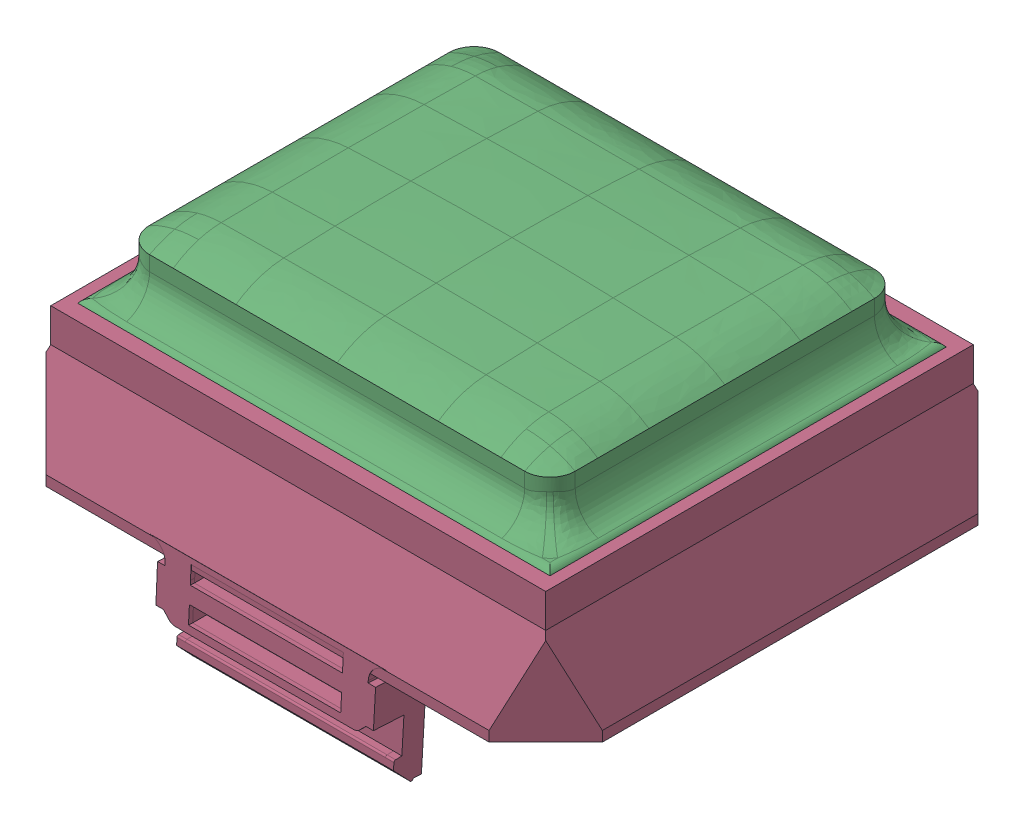
SolidWorks assembly ChessBDesign, configuration 默认. Lengths in mm.
Overall size (33 18.27 29.5).
5 component instances, 5 part files, 13 mates.
Components (placement in the parent):
- ChessBLens-1: ChessBLens [默认] at origin size (28.33 2.18 23.83)
- ChessBInsideSkin-1: ChessBInsideSkin [默认] at (0.0001 0 0.2499) size (23.8 5.48 19.29)
- ChessBTopskin-1: ChessBTopskin [默认] at (0.0001 2 0.2499) size (28.02 6.25 23.52)
- ChessBSupportbase-2: ChessBSupportbase [默认] at origin size (33 14.02 29.5)
- ChessBChessboardMarker-1: ChessBChessboardMarker [默认] at (-4.7946 24.2 -14.5409) x (1 0 0) z (0 -1 0) size (22.6 16.44 0.67)
Mates (geometry in assembly coordinates):
- 同心2: concentric anti-aligned: cylinder of InsideSkin-1 through (10.8751 17.7531 8.6249) axis (0 1 0) radius 0.7; cylinder of Board3Con1612611OriginalSkin_TOP-1 through (10.8751 24 8.6249) axis (0 -1 0) radius 0.7
- 同心3: concentric anti-aligned: cylinder of InsideSkin-1 through (10.8751 17.7531 -9.1251) axis (0 1 0) radius 0.7; cylinder of Board3Con1612611OriginalSkin_TOP-1 through (10.8751 24 -9.1251) axis (0 -1 0) radius 0.7
- 重合4: coincident aligned: plane of InsideSkin-1 through (10.8751 19 -9.1251) normal (0 -1 0); plane of Board3Con1612611OriginalSkin_TOP-1 through (0.0001 19 0.2499) normal (0 -1 0)
- 重合6: coordinate: point of NewContiSupportBase-2
- 重合7: coincident anti-aligned: plane of lensall-1 through (13.75 19 -11.5) normal (0.939693 0.34202 0); plane of NewContiSupportBase-2 through (13.75 19 12.7803) normal (-0.939693 -0.34202 0)
- 同心5: concentric aligned: cylinder of lensall-1 through (13.3294 18.6938 -11.0794) axis (-0.323616 0.889126 0.323616) radius 0.5; cylinder of NewContiSupportBase-2 through (10.7866 25.6801 -8.5366) axis (-0.323616 0.889126 0.323616) radius 0.5
- 重合8: coincident anti-aligned: plane of lensall-1 through (0 18 0) normal (0 -1 0); plane of NewContiSupportBase-2 through (0 18 0) normal (0 1 0)
- 重合9: coincident anti-aligned: plane of lensall-1 through (0 19 0) normal (0 1 0); plane of Board3Con1612611OriginalSkin_TOP-1 through (0.0001 19 0.2499) normal (0 -1 0)
- 重合10: coincident anti-aligned: plane of Board3Con1612611OriginalSkin_TOP-1 through (0.0001 19 11.7499) normal (0 0 1); plane of NewContiSupportBase-2 through (-13.5999 21 11.7499) normal (0 0 -1)
- 重合11: coincident anti-aligned: plane of Board3Con1612611OriginalSkin_TOP-1 through (14.0001 19 0.2499) normal (1 0 0); plane of NewContiSupportBase-2 through (14.0001 21 11.7499) normal (-1 0 0)
- 宽度1: width aligned: plane of InsideSkin-1 through (-11.3749 17.7531 9.3249) normal (0 0 1); plane of ChessboardMarker-1 through (-11.3749 17.7531 -9.8251) normal (0 0 -1); plane of InsideSkin-1 through (2.8501 23.8 7.9249) normal (0 0 1); plane of ChessboardMarker-1 through (0.8001 23.8 -8.4251) normal (0 0 -1)
- 宽度2: width aligned: plane of InsideSkin-1 through (11.5751 17.7531 -9.1251) normal (1 0 0); plane of ChessboardMarker-1 through (-12.0749 17.7531 -9.1251) normal (-1 0 0); plane of InsideSkin-1 through (11.0001 23.8 -6.4251) normal (1 0 0); plane of ChessboardMarker-1 through (-11.4999 23.8 -6.4251) normal (-1 0 0)
- 距离1: distance = 4.8 mm anti-aligned: plane of Lens-1 through (0 19 0) normal (0 1 0); plane of ChessboardMarker-1 through (-4.7946 23.8 -10.4409) normal (0 -1 0)
